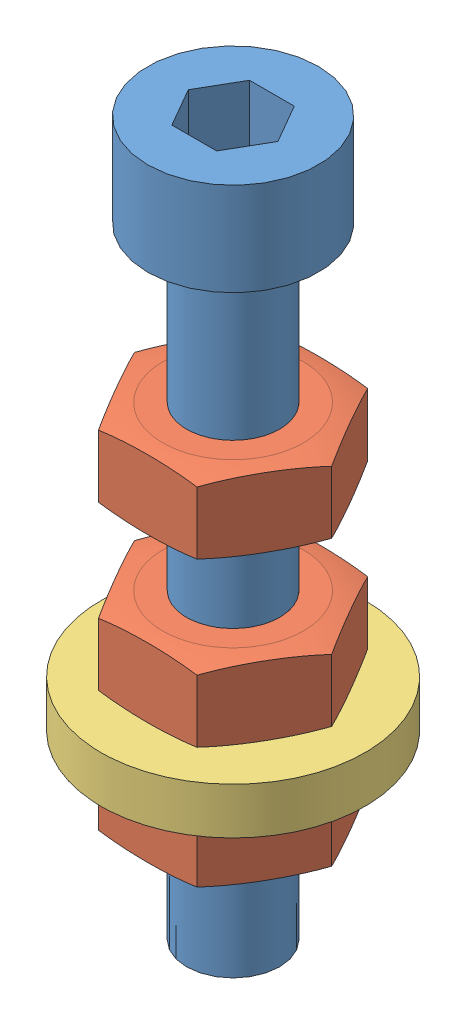
SolidWorks assembly M3_assembly_push, configuration Valor predeterminado. Lengths in mm.
Overall size (8.5 23 8.5).
5 component instances, 3 part files, 9 mates.
Components (placement in the parent):
- M3_cap_screw-1: M3_cap_screw [Valor predeterminado] at origin size (5.5 23 5.5)
- M3_nut-1: M3_nut [Valor predeterminado] at (0 -10.4 0) size (6.35 3.17 5.5)
- M3_nut-2: M3_nut [Valor predeterminado] at (0 -19.55 0) size (6.35 3.17 5.5)
- M3_nut-3: M3_nut [Valor predeterminado] at (0 -15.65 0) size (6.35 3.17 5.5)
- arruela_m3-1: arruela_m3 [Valor predeterminado] at (0 -17.15 0) size (8.5 1.5 8.5)
Mates (geometry in assembly coordinates):
- Concêntrico1: concentric anti-aligned: cylinder of M3_cap_screw-1 through (0 -23 0) axis (0 1 0) radius 1.5; cylinder of M3_nut-1 through (0 -5 0) axis (0 -1 0) radius 1.5
- Concêntrico2: concentric anti-aligned: cylinder of M3_cap_screw-1 through (0 -23 0) axis (0 1 0) radius 1.5; cylinder of M3_nut-3 through (0 -10.25 0) axis (0 -1 0) radius 1.5
- Concêntrico3: concentric anti-aligned: cylinder of M3_cap_screw-1 through (0 -23 0) axis (0 1 0) radius 1.5; cylinder of M3_nut-2 through (0 -14.15 0) axis (0 -1 0) radius 1.5
- Distância4: distance = 5 mm anti-aligned: plane of M3_cap_screw-1 through (0 -3 0) normal (0 -1 0); plane of M3_nut-1 through (0 -8 0) normal (0 1 0)
- Distância2: distance = 1.5 mm anti-aligned: plane of M3_nut-3 through (0 -15.65 0) normal (0 -1 0); plane of M3_nut-2 through (0 -17.15 0) normal (0 1 0)
- Concêntrico4: concentric anti-aligned: cylinder of M3_cap_screw-1 through (0 -23 0) axis (0 1 0) radius 1.5; cylinder of arruela_m3-1 through (0 -12.65 0) axis (0 -1 0) radius 1.75
- Coincidente1: coincident aligned: plane of arruela_m3-1 through (0 -14.15 0) normal (0 0 1)
- Coincidente3: coincident anti-aligned: plane of M3_nut-2 through (0 -14.15 0) normal (0 1 0); plane of arruela_m3-1 through (0 -14.15 0) normal (0 -1 0)
- Distância3: distance = 5.25 mm anti-aligned: plane of arruela_m3-1 through (0 -15.65 0) normal (0 1 0); plane of M3_nut-1 through (0 -10.4 0) normal (0 -1 0)
